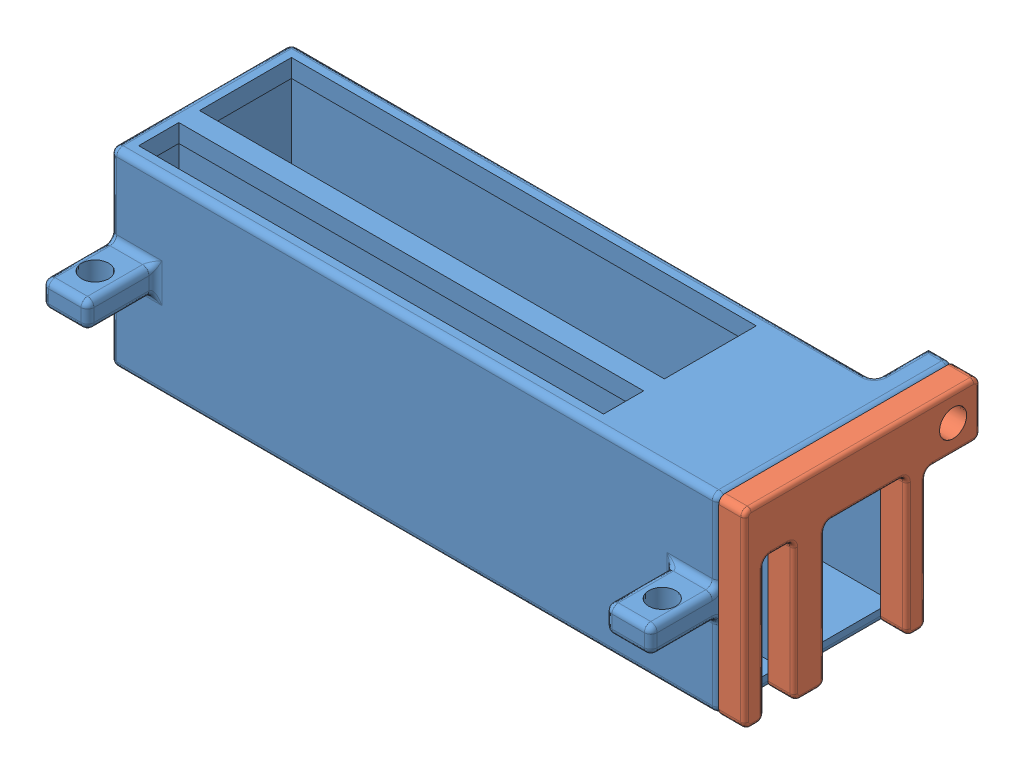
SolidWorks assembly USB-holder-assy-v2, configuration Default. Lengths in mm.
Overall size (124.46 37.34 46.23).
2 component instances, 2 part files, 0 mates.
Components (placement in the parent):
- USB-holder-box-v4-1: USB-holder-box-v4 [Default] at (45.243 44.2356 89.5298) size (119.38 37.34 35.56)
- USB-holder-cover-v2-1: USB-holder-cover-v2 [Default] at origin size (5.08 37.34 46.23)
